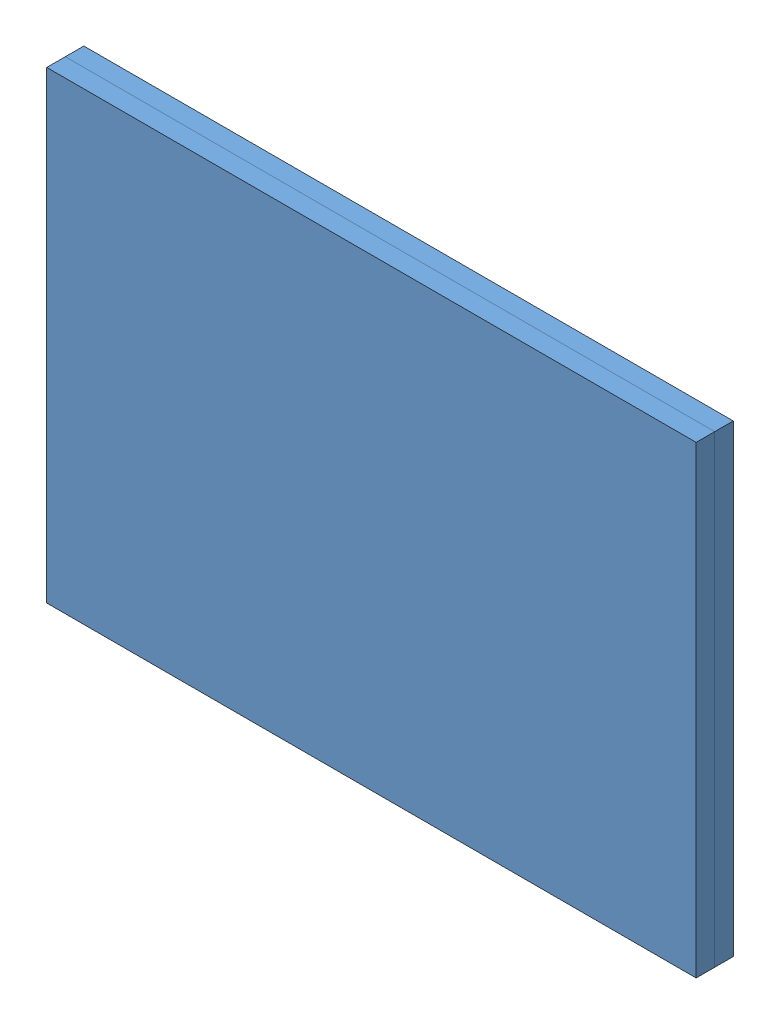
SolidWorks assembly Baugruppe1, configuration Standard. Lengths in mm.
Overall size (70 50 4).
2 component instances, 1 part files, 3 mates.
Components (placement in the parent):
- Teil2-1: Teil2 [Standard] at (-41.3291 -39.0223 -1) size (70 50 2)
- Teil2-2: Teil2 [Standard] at (-41.3291 -39.0223 1) size (70 50 2)
Mates (geometry in assembly coordinates):
- Deckungsgleich1: coincident: plane of Teil2-1 through (28.6709 -39.0223 1) normal (1 0 0); plane of Teil2-2 through (28.6709 46.6619 36.0804) normal (1 0 0)
- Deckungsgleich2: coincident: line of Teil2-1 through (28.6709 10.9777 1) axis (-1 0 0); line of Teil2-2 through (28.6709 10.9777 1) axis (-1 0 0)
- LimitWinkel1: limit planar angle = 0.816844 rad: plane of Teil2-2 through (-41.3291 10.9777 1) normal (0 0 -1); plane of Teil2-1 through (-41.3291 10.9777 1) normal (0 0 1)
